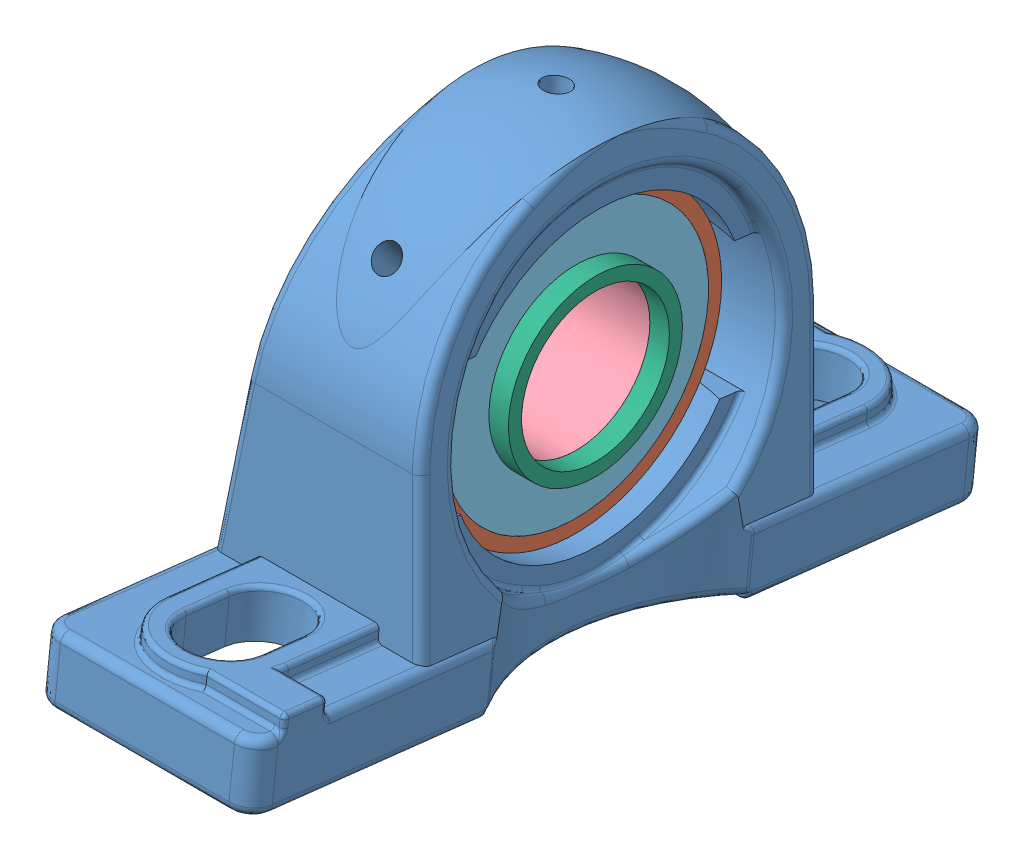
SolidWorks assembly PBB unit.assem, configuration Default. Lengths in mm.
Overall size (50.31 116.05 179.94).
18 component instances, 7 part files, 3 mates.
Components (placement in the parent):
- Pillow block-1: Pillow block [Default] at (-19.5799 46.3943 193.3673) x (0 -0.113203 -0.993572) z (1 0 0) size (170 97.43 50.31)
- PB bearing-1: PB bearing [Default] at (-19.5799 54.3428 192.4617) size (36.5 72.34 70.23)
  - PB outer-1: PB outer [Default] at origin size (20 68.56 69.24)
  - PB Ball-1: PB Ball [Default] at (0 -4.1637 -25.6644) x (1 0 0) z (0 -0.951057 -0.309017) size (15 15 15)
  - PB Ball-2: PB Ball [Default] at (0 -25.695 -3.9709) x (1 0 0) z (0 -0.587785 0.809017) size (15 15 15)
  - PB Ball-3: PB Ball [Default] at (0 25.695 3.9709) x (1 0 0) z (0 0.587785 -0.809017) size (15 15 15)
  - PB Ball-4: PB Ball [Default] at (0 -11.7167 23.2103) x (1 0 0) z (0 0.587785 0.809017) size (15 15 15)
  - PB Ball-5: PB Ball [Default] at (0 11.7167 -23.2103) x (1 0 0) z (0 -0.587785 -0.809017) size (15 15 15)
  - PB Ball-6: PB Ball [Default] at (0 23.1217 -11.8906) x (1 0 0) z (0 0 -1) size (15 15 15)
  - PB Ball-7: PB Ball [Default] at (0 18.4537 18.3156) x (1 0 0) z (0 0.951057 -0.309017) size (15 15 15)
  - PB Ball-8: PB Ball [Default] at (0 -23.1217 11.8906) size (15 15 15)
  - PB Ball-9: PB Ball [Default] at (0 4.1637 25.6644) x (1 0 0) z (0 0.951057 0.309017) size (15 15 15)
  - PB Ball-10: PB Ball [Default] at (0 -18.4537 -18.3156) x (1 0 0) z (0 -0.951057 0.309017) size (15 15 15)
  - PB inner-1: PB inner [Default] at origin size (20 40 40)
  - PB side cover-1: PB side cover [Default] at (10 0 0) x (0 -1 0) z (0 0 -1) size (61 1 61)
  - PB side cover-2: PB side cover [Default] at (-10 0 0) x (0 -1 0) z (0 0 1) size (61 1 61)
  - Rall inner ring A-1: Rall inner ring A [Default] at (10 0 0) x (0 -1 0) z (0 0 1) size (40 4.5 40)
  - Rall inner ring B-1: Rall inner ring B [Default] at (-22 0 0) x (0 -1 0) z (0 0 1) size (40 12 40)
Mates (geometry in assembly coordinates):
- Width1: width: plane of Pillow block-1 through (4.4201 15.3541 150.6063) normal (0.993572 0.112476 -0.012815); plane of PB bearing-1/PB outer-1 through (-43.5799 15.3541 150.6063) normal (-0.993572 0.112476 -0.012815); plane of Pillow block-1 through (-29.5799 54.3428 158.9617) normal (-1 0 0); plane of PB bearing-1/PB outer-1 through (-9.5799 54.3428 158.9617) normal (1 0 0)
- Parallel1: parallel aligned: plane of Pillow block-1 through (-34.5799 54.3428 192.4617) normal (-1 0 0); plane of PB bearing-1/Rall inner ring B-1 through (-41.5799 54.3428 192.4617) normal (-1 0 0)
- Concentric1: concentric aligned: cylinder of Pillow block-1 through (-24.5799 54.3428 192.4617) axis (-1 0 0) radius 32.5; cylinder of PB bearing-1/PB inner-1 through (-19.5799 54.3428 192.4617) axis (-1 0 0) radius 17
